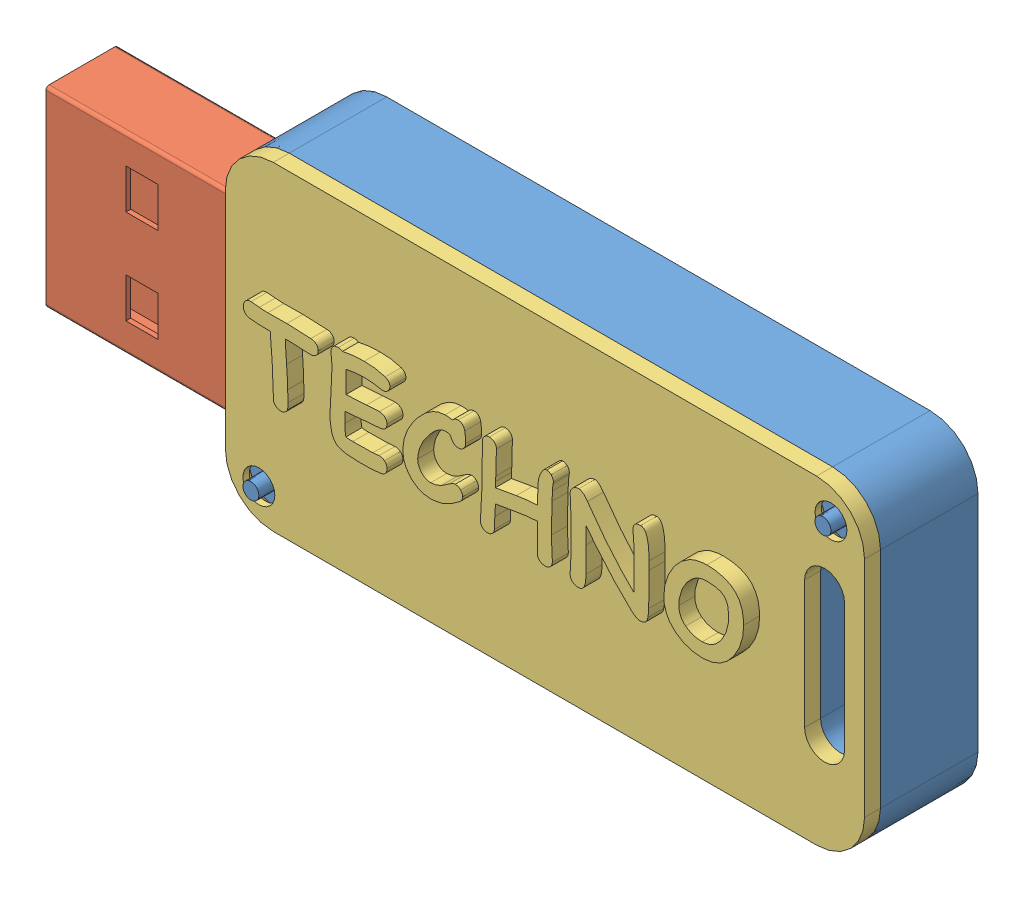
SolidWorks assembly cle_usb_2Go, configuration Défaut. Lengths in mm.
Overall size (52.22 20 8.1).
3 component instances, 3 part files, 5 mates.
Components (placement in the parent):
- face_arriere-1: face_arriere [Défaut] at origin size (40 20 7.6)
- cle_2Go-1: cle_2Go [Défaut] at (-24.81 0 6.1) x (1 0 0) z (0 0 -1) size (44.82 14 4.5)
- face_avant-1: face_avant [Défaut] at (0 0 7.1) size (40 20 2)
Mates (geometry in assembly coordinates):
- Coïncidente6: coincident aligned: plane of face_arriere-1 through (20 -10 6.1) normal (0 0 1); plane of cle_2Go-1 through (-17.4 6 6.1) normal (0 0 1)
- Coaxiale7: concentric aligned: cylinder of face_arriere-1 through (11.1 -5.4 4.1) axis (0 0 -1) radius 0.4; cylinder of cle_2Go-1 through (11.1 -5.4 6.1) axis (0 0 -1) radius 0.7
- Coaxiale8: concentric aligned: cylinder of face_arriere-1 through (11.1 5.4 4.1) axis (0 0 -1) radius 0.4; cylinder of cle_2Go-1 through (11.1 5.4 6.1) axis (0 0 -1) radius 0.7
- Coaxiale9: concentric anti-aligned: cylinder of face_arriere-1 through (-17.9 -8 7.6) axis (0 0 -1) radius 0.5; cylinder of face_avant-1 through (-17.9 -8 6.1) axis (0 0 1) radius 1
- Coïncidente8: coincident anti-aligned: plane of face_arriere-1 through (20 -10 6.1) normal (0 0 1); plane of face_avant-1 through (-17 -7 6.1) normal (0 0 -1)
